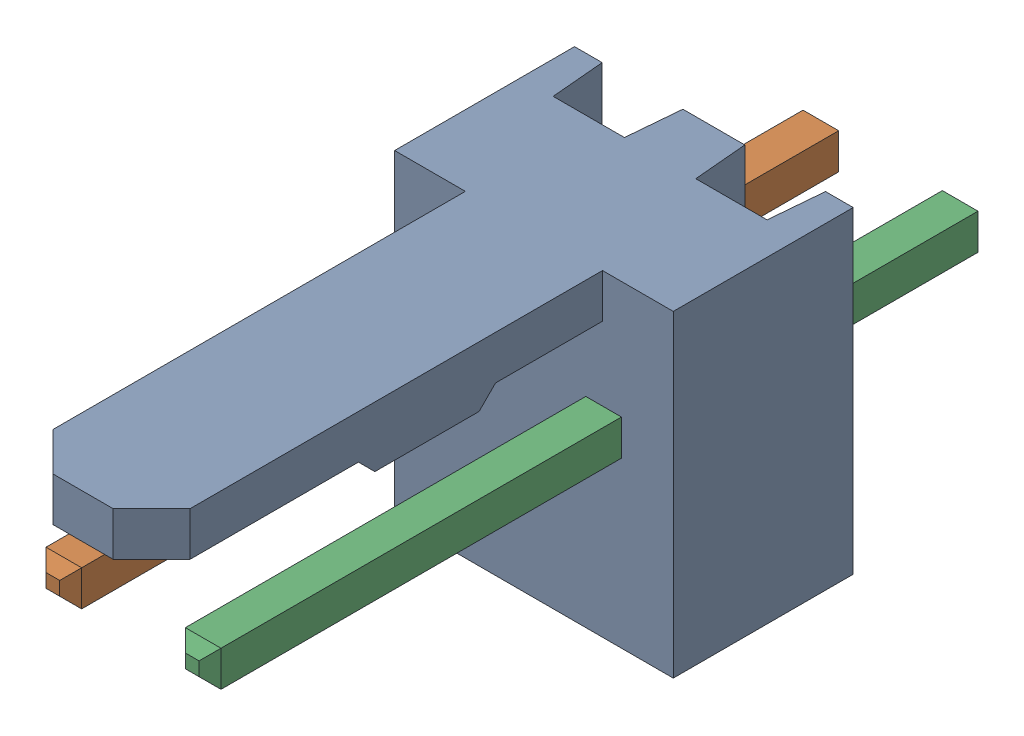
SolidWorks assembly Molex PCB 2 pin v2, configuration Default. Lengths in mm.
Overall size (5.08 5.79 14.92).
3 component instances, 2 part files, 0 mates.
Components (placement in the parent):
- BASE9710016-1: BASE9710016 [Default] at (2.54 2.895 -8.22) size (5.08 5.79 11.5)
- PINO9710016-1: PINO9710016 [Default] at (1.27 3.325 -0.72) size (0.65 0.65 14.2)
- PINO9710016-2: PINO9710016 [Default] at (3.81 3.325 -0.72) size (0.65 0.65 14.2)
